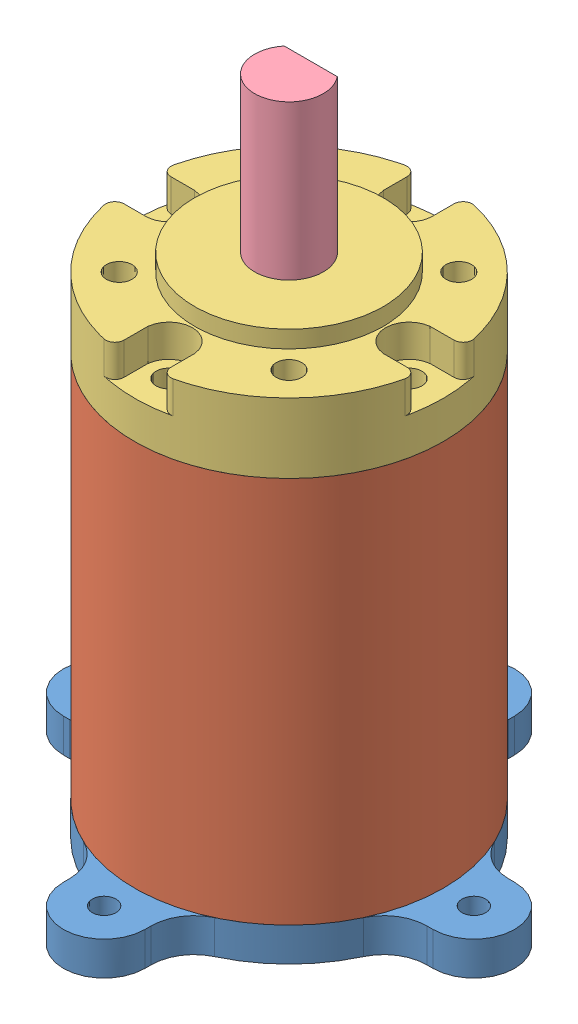
SolidWorks assembly 36mm 47.1(263_1) gear box, configuration Default. Lengths in mm.
Overall size (52.63 77.16 52.63).
4 component instances, 4 part files, 0 mates.
Components (placement in the parent):
- 251916mount_36mm gearbox.step-1: 251916mount_36mm gearbox.step [Default] at (0 2.413 0) size (52.63 6.35 52.63)
- 36mm 47.1(263_1) gear box.step-1: 36mm 47.1(263_1) gear box.step [Default] at origin size (36 45.1 36)
- 36mm 47.1(263_1) gear box-0.step-1: 36mm 47.1(263_1) gear box-0.step [Default] at origin size (36 10.13 36)
- 36mm 47.1(263_1) gear box-1.step-1: 36mm 47.1(263_1) gear box-1.step [Default] at origin size (8 20 8)
